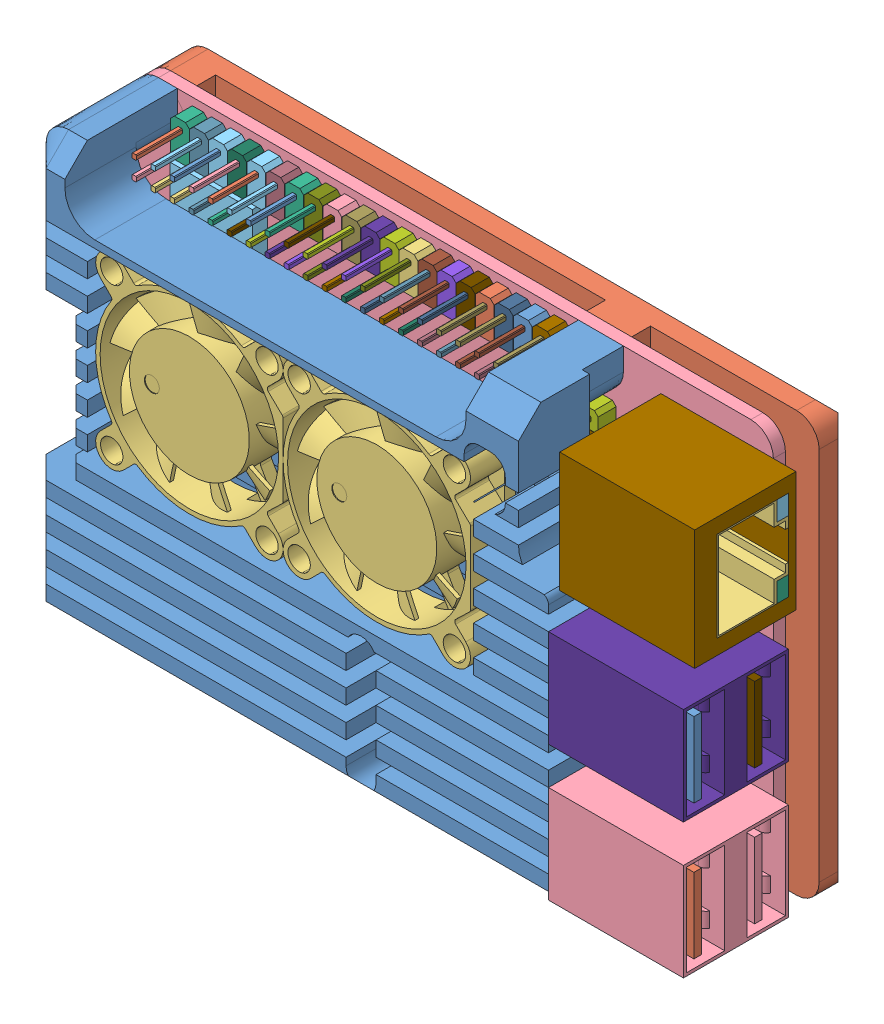
SolidWorks assembly Raspberry, configuration Predeterminado. Lengths in mm.
Overall size (88 57 24.1).
127 component instances, 125 part files, 0 mates.
Components (placement in the parent):
- full raspberry pi 4 upgrade cooling.step-1: full raspberry pi 4 upgrade cooling.step [Predeterminado] at origin size (88 57 24.1)
  - радиатор верх.step-1: радиатор верх.step [Predeterminado] at (70 0 7.1) size (70 56 15)
  - радиатор низ.step-1: радиатор низ.step [Predeterminado] at (0 0 -2.5) x (0 1 0) z (0 0 -1) size (56 87 7.5)
  - вентилятор.step-1: вентилятор.step [Predeterminado] at (46.1053 34.1447 9.6) x (0 -1 0) z (0 0 -1) size (25 25 6)
  - вентилятор.step-2: вентилятор.step [Predeterminado] at (21.1053 34.1447 9.6) x (0 -1 0) z (0 0 -1) size (25 25 6)
  - распбери 4.step-1: распбери 4.step [Predeterminado] at origin size (85 56 1.6)
  - распбери 4-0.step-1: распбери 4-0.step [Predeterminado] at origin size (2.5 5 2.4)
  - распбери 4-1.step-1: распбери 4-1.step [Predeterminado] at origin size (2.5 5 2.4)
  - распбери 4-2.step-1: распбери 4-2.step [Predeterminado] at origin size (2.5 5 2.4)
  - распбери 4-3.step-1: распбери 4-3.step [Predeterminado] at origin size (2.5 5 2.4)
  - распбери 4-4.step-1: распбери 4-4.step [Predeterminado] at origin size (2.5 5 2.4)
  - распбери 4-5.step-1: распбери 4-5.step [Predeterminado] at origin size (2.5 5 2.4)
  - распбери 4-6.step-1: распбери 4-6.step [Predeterminado] at origin size (2.5 5 2.4)
  - распбери 4-7.step-1: распбери 4-7.step [Predeterminado] at origin size (2.5 5 2.4)
  - распбери 4-8.step-1: распбери 4-8.step [Predeterminado] at origin size (2.5 5 2.4)
  - распбери 4-9.step-1: распбери 4-9.step [Predeterminado] at origin size (2.5 5 2.4)
  - распбери 4-10.step-1: распбери 4-10.step [Predeterminado] at origin size (2.5 5 2.4)
  - распбери 4-11.step-1: распбери 4-11.step [Predeterminado] at origin size (2.5 5 2.4)
  - распбери 4-12.step-1: распбери 4-12.step [Predeterminado] at origin size (2.5 5 2.4)
  - распбери 4-13.step-1: распбери 4-13.step [Predeterminado] at origin size (2.5 5 2.4)
  - распбери 4-14.step-1: распбери 4-14.step [Predeterminado] at origin size (2.5 5 2.4)
  - распбери 4-15.step-1: распбери 4-15.step [Predeterminado] at origin size (2.5 5 2.4)
  - распбери 4-16.step-1: распбери 4-16.step [Predeterminado] at origin size (2.5 5 2.4)
  - распбери 4-17.step-1: распбери 4-17.step [Predeterminado] at origin size (2.5 5 2.4)
  - распбери 4-18.step-1: распбери 4-18.step [Predeterminado] at origin size (2.5 5 2.4)
  - распбери 4-19.step-1: распбери 4-19.step [Predeterminado] at origin size (2.5 5 2.4)
  - распбери 4-20.step-1: распбери 4-20.step [Predeterminado] at origin size (2.5 2.5 2.4)
  - распбери 4-21.step-1: распбери 4-21.step [Predeterminado] at origin size (2.5 2.5 2.4)
  - распбери 4-22.step-1: распбери 4-22.step [Predeterminado] at origin size (2.5 2.5 2.4)
  - распбери 4-23.step-1: распбери 4-23.step [Predeterminado] at origin size (2.5 2.5 2.4)
  - распбери 4-24.step-1: распбери 4-24.step [Predeterminado] at origin size (0.65 0.65 11.5)
  - распбери 4-25.step-1: распбери 4-25.step [Predeterminado] at origin size (0.65 0.65 11.5)
  - распбери 4-26.step-1: распбери 4-26.step [Predeterminado] at origin size (0.65 0.65 11.5)
  - распбери 4-27.step-1: распбери 4-27.step [Predeterminado] at origin size (0.65 0.65 11.5)
  - распбери 4-28.step-1: распбери 4-28.step [Predeterminado] at origin size (0.65 0.65 11.5)
  - распбери 4-29.step-1: распбери 4-29.step [Predeterminado] at origin size (0.65 0.65 11.5)
  - распбери 4-30.step-1: распбери 4-30.step [Predeterminado] at origin size (0.65 0.65 11.5)
  - распбери 4-31.step-1: распбери 4-31.step [Predeterminado] at origin size (0.65 0.65 11.5)
  - распбери 4-32.step-1: распбери 4-32.step [Predeterminado] at origin size (0.65 0.65 11.5)
  - распбери 4-33.step-1: распбери 4-33.step [Predeterminado] at origin size (0.65 0.65 11.5)
  - распбери 4-34.step-1: распбери 4-34.step [Predeterminado] at origin size (0.65 0.65 11.5)
  - распбери 4-35.step-1: распбери 4-35.step [Predeterminado] at origin size (0.65 0.65 11.5)
  - распбери 4-36.step-1: распбери 4-36.step [Predeterminado] at origin size (0.65 0.65 11.5)
  - распбери 4-37.step-1: распбери 4-37.step [Predeterminado] at origin size (0.65 0.65 11.5)
  - распбери 4-38.step-1: распбери 4-38.step [Predeterminado] at origin size (0.65 0.65 11.5)
  - распбери 4-39.step-1: распбери 4-39.step [Predeterminado] at origin size (0.65 0.65 11.5)
  - распбери 4-40.step-1: распбери 4-40.step [Predeterminado] at origin size (0.65 0.65 11.5)
  - распбери 4-41.step-1: распбери 4-41.step [Predeterminado] at origin size (0.65 0.65 11.5)
  - распбери 4-42.step-1: распбери 4-42.step [Predeterminado] at origin size (0.65 0.65 11.5)
  - распбери 4-43.step-1: распбери 4-43.step [Predeterminado] at origin size (0.65 0.65 11.5)
  - распбери 4-44.step-1: распбери 4-44.step [Predeterminado] at origin size (0.65 0.65 11.5)
  - распбери 4-45.step-1: распбери 4-45.step [Predeterminado] at origin size (0.65 0.65 11.5)
  - распбери 4-46.step-1: распбери 4-46.step [Predeterminado] at origin size (0.65 0.65 11.5)
  - распбери 4-47.step-1: распбери 4-47.step [Predeterminado] at origin size (0.65 0.65 11.5)
  - распбери 4-48.step-1: распбери 4-48.step [Predeterminado] at origin size (0.65 0.65 11.5)
  - распбери 4-49.step-1: распбери 4-49.step [Predeterminado] at origin size (0.65 0.65 11.5)
  - распбери 4-50.step-1: распбери 4-50.step [Predeterminado] at origin size (0.65 0.65 11.5)
  - распбери 4-51.step-1: распбери 4-51.step [Predeterminado] at origin size (0.65 0.65 11.5)
  - распбери 4-52.step-1: распбери 4-52.step [Predeterminado] at origin size (0.65 0.65 11.5)
  - распбери 4-53.step-1: распбери 4-53.step [Predeterminado] at origin size (0.65 0.65 11.5)
  - распбери 4-54.step-1: распбери 4-54.step [Predeterminado] at origin size (0.65 0.65 11.5)
  - распбери 4-55.step-1: распбери 4-55.step [Predeterminado] at origin size (0.65 0.65 11.5)
  - распбери 4-56.step-1: распбери 4-56.step [Predeterminado] at origin size (0.65 0.65 11.5)
  - распбери 4-57.step-1: распбери 4-57.step [Predeterminado] at origin size (0.65 0.65 11.5)
  - распбери 4-58.step-1: распбери 4-58.step [Predeterminado] at origin size (0.65 0.65 11.5)
  - распбери 4-59.step-1: распбери 4-59.step [Predeterminado] at origin size (0.65 0.65 11.5)
  - распбери 4-60.step-1: распбери 4-60.step [Predeterminado] at origin size (0.65 0.65 11.5)
  - распбери 4-61.step-1: распбери 4-61.step [Predeterminado] at origin size (0.65 0.65 11.5)
  - распбери 4-62.step-1: распбери 4-62.step [Predeterminado] at origin size (0.65 0.65 11.5)
  - распбери 4-63.step-1: распбери 4-63.step [Predeterminado] at origin size (0.65 0.65 11.5)
  - распбери 4-64.step-1: распбери 4-64.step [Predeterminado] at origin size (0.65 0.65 11.5)
  - распбери 4-65.step-1: распбери 4-65.step [Predeterminado] at origin size (0.65 0.65 11.5)
  - распбери 4-66.step-1: распбери 4-66.step [Predeterminado] at origin size (0.65 0.65 11.5)
  - распбери 4-67.step-1: распбери 4-67.step [Predeterminado] at origin size (0.65 0.65 11.5)
  - распбери 4-68.step-1: распбери 4-68.step [Predeterminado] at origin size (0.8 14 5)
  - распбери 4-69.step-1: распбери 4-69.step [Predeterminado] at origin size (2.5 20 5)
  - распбери 4-70.step-1: распбери 4-70.step [Predeterminado] at origin size (2.5 20 5)
  - распбери 4-71.step-1: распбери 4-71.step [Predeterminado] at origin size (0.8 14 5)
  - распбери 4-72.step-1: распбери 4-72.step [Predeterminado] at origin size (11 13 2)
  - распбери 4-73.step-1: распбери 4-73.step [Predeterminado] at origin size (15 15 2.5)
  - распбери 4-74.step-1: распбери 4-74.step [Predeterminado] at origin size (10 15 1)
  - распбери 4-75.step-1: распбери 4-75.step [Predeterminado] at origin size (8 8 1)
  - распбери 4-76.step-1: распбери 4-76.step [Predeterminado] at origin size (6 6 1)
  - распбери 4-77.step-1: распбери 4-77.step [Predeterminado] at origin size (4.5 7 2)
  - распбери 4-78.step-1: распбери 4-78.step [Predeterminado] at origin size (9 7 3)
  - распбери 4-79.step-1: распбери 4-79.step [Predeterminado] at origin size (6.5 7 3)
  - распбери 4-80.step-1: распбери 4-80.step [Predeterminado] at origin size (6.5 7 3)
  - распбери 4-81.step-1: распбери 4-81.step [Predeterminado] at origin size (6.5 0.5 3)
  - распбери 4-82.step-1: распбери 4-82.step [Predeterminado] at origin size (7 12.5 6)
  - распбери 4-83.step-1: распбери 4-83.step [Predeterminado] at origin size (6 1 6)
  - распбери 4-84.step-1: распбери 4-84.step [Predeterminado] at origin size (18 13 15)
  - распбери 4-85.step-1: распбери 4-85.step [Predeterminado] at origin size (9 10 1)
  - распбери 4-86.step-1: распбери 4-86.step [Predeterminado] at origin size (9 10 1)
  - распбери 4-87.step-1: распбери 4-87.step [Predeterminado] at origin size (9 10 1)
  - распбери 4-88.step-1: распбери 4-88.step [Predeterminado] at origin size (9 12 9.5)
  - распбери 4-89.step-1: распбери 4-89.step [Predeterminado] at origin size (9 10 1)
  - распбери 4-90.step-1: распбери 4-90.step [Predeterminado] at origin size (3 2.6 1.5)
  - распбери 4-91.step-1: распбери 4-91.step [Predeterminado] at origin size (3 2.6 1.5)
  - распбери 4-92.step-1: распбери 4-92.step [Predeterminado] at origin size (6 2.6 1.5)
  - распбери 4-93.step-1: распбери 4-93.step [Predeterminado] at origin size (6 2.6 1.5)
  - распбери 4-94.step-1: распбери 4-94.step [Predeterminado] at origin size (18 16 13.5)
  - распбери 4-95.step-1: распбери 4-95.step [Predeterminado] at origin size (8 12.2 5.1)
  - распбери 4-96.step-1: распбери 4-96.step [Predeterminado] at origin size (7 1.2 0.6)
  - распбери 4-97.step-1: распбери 4-97.step [Predeterminado] at origin size (7 1.2 0.6)
  - распбери 4-98.step-1: распбери 4-98.step [Predeterminado] at origin size (7 1.2 0.6)
  - распбери 4-99.step-1: распбери 4-99.step [Predeterminado] at origin size (7 1.2 0.6)
  - распбери 4-100.step-1: распбери 4-100.step [Predeterminado] at origin size (7 1.2 0.6)
  - распбери 4-101.step-1: распбери 4-101.step [Predeterminado] at origin size (7 1.2 0.6)
  - распбери 4-102.step-1: распбери 4-102.step [Predeterminado] at origin size (7 1.2 0.6)
  - распбери 4-103.step-1: распбери 4-103.step [Predeterminado] at origin size (7 1.2 0.6)
  - распбери 4-104.step-1: распбери 4-104.step [Predeterminado] at origin size (7 1.2 0.6)
  - распбери 4-105.step-1: распбери 4-105.step [Predeterminado] at origin size (7 1.2 0.6)
  - распбери 4-106.step-1: распбери 4-106.step [Predeterminado] at origin size (7 1.2 0.6)
  - распбери 4-107.step-1: распбери 4-107.step [Predeterminado] at origin size (18 13 15)
  - распбери 4-108.step-1: распбери 4-108.step [Predeterminado] at origin size (7 1.2 0.6)
  - распбери 4-109.step-1: распбери 4-109.step [Predeterminado] at origin size (13 11 1)
  - распбери 4-110.step-1: распбери 4-110.step [Predeterminado] at origin size (13 11 1)
  - распбери 4-111.step-1: распбери 4-111.step [Predeterminado] at origin size (7 0.6 0.2)
  - распбери 4-112.step-1: распбери 4-112.step [Predeterminado] at origin size (7 0.6 0.2)
  - распбери 4-113.step-1: распбери 4-113.step [Predeterminado] at origin size (7 0.6 0.2)
  - распбери 4-114.step-1: распбери 4-114.step [Predeterminado] at origin size (7 0.6 0.2)
  - распбери 4-115.step-1: распбери 4-115.step [Predeterminado] at origin size (7 0.6 0.2)
  - распбери 4-116.step-1: распбери 4-116.step [Predeterminado] at origin size (7 0.6 0.2)
  - распбери 4-117.step-1: распбери 4-117.step [Predeterminado] at origin size (7 0.6 0.2)
  - распбери 4-118.step-1: распбери 4-118.step [Predeterminado] at origin size (7 0.6 0.2)
  - распбери 4-119.step-1: распбери 4-119.step [Predeterminado] at origin size (8.63 10.92 0.05)
  - распбери 4-120.step-1: распбери 4-120.step [Predeterminado] at origin size (11 12 1.4)
